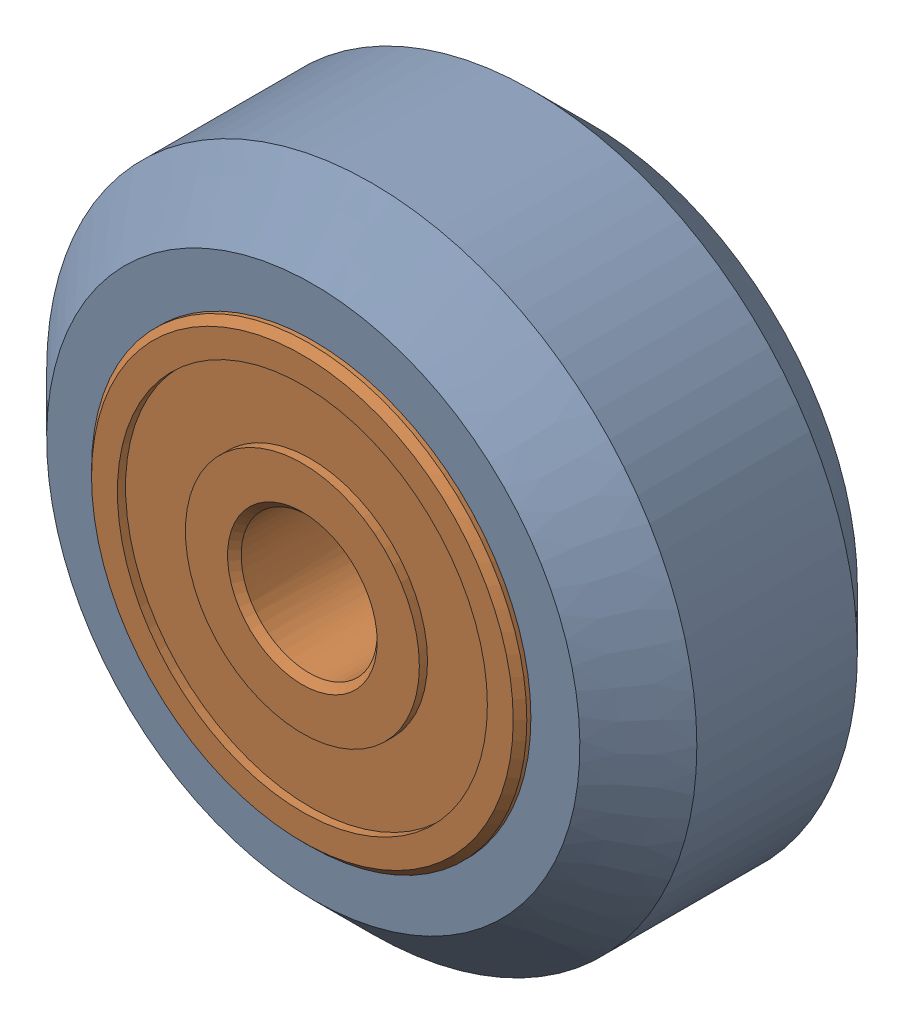
SolidWorks assembly Xtreme Solid V Wheel Assembly_1, configuration Default. Lengths in mm.
Overall size (23.9 23.9 11).
3 component instances, 2 part files, 0 mates.
Components (placement in the parent):
- Xtreme Solid V Wheel-1: Xtreme Solid V Wheel [Default] at (-45.15 -55 30) x (0 0 1) z (-1 0 0) size (10.2 23.9 23.9)
- Wheel+Kit+-+5x16x5mm+Sealed+Radial+Ball+Bearing.step.f3d-1: Wheel+Kit+-+5x16x5mm+Sealed+Radial+Ball+Bearing.step.f3d [Default] at (-45.15 -55 30) x (0 1 0) z (-1 0 0) size (16 5 16)
- Wheel+Kit+-+5x16x5mm+Sealed+Radial+Ball+Bearing.step.f3d-2: Wheel+Kit+-+5x16x5mm+Sealed+Radial+Ball+Bearing.step.f3d [Default] at (-45.15 -55 30) x (0 1 0) z (1 0 0) size (16 5 16)
